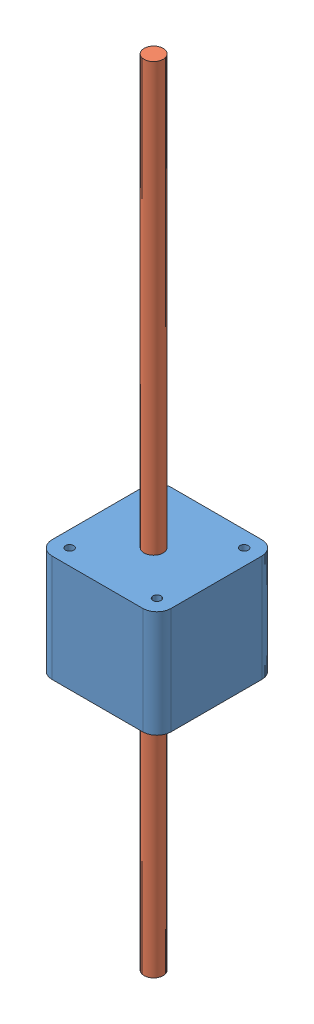
SolidWorks assembly Stepper, configuration Default. Lengths in mm.
Overall size (42.3 282 42.3).
2 component instances, 2 part files, 2 mates.
Components (placement in the parent):
- Stepper Base-1: Stepper Base [Default] at (-15.2672 25.2726 22.8224) size (42.3 38 42.3)
- Stepper Shaft-1: Stepper Shaft [Default] at (-21.9609 -66.8103 34.4775) x (-0.999993 0 0.003774) z (-0.003774 0 -0.999993) size (6.8 282 6.8)
Mates (geometry in assembly coordinates):
- Screw2: screw = 2 mm anti-aligned: cylinder of Stepper Base-1 through (-21.9609 63.2726 34.4775) axis (0 1 0) radius 3.4; cylinder of Stepper Shaft-1 through (-21.9609 215.1897 34.4775) axis (0 -1 0) radius 3.4
- Concentric2: concentric anti-aligned: circle of Stepper Base-1; cylinder of Stepper Shaft-1 through (-21.9609 215.1897 34.4775) axis (0 -1 0) radius 3.4
